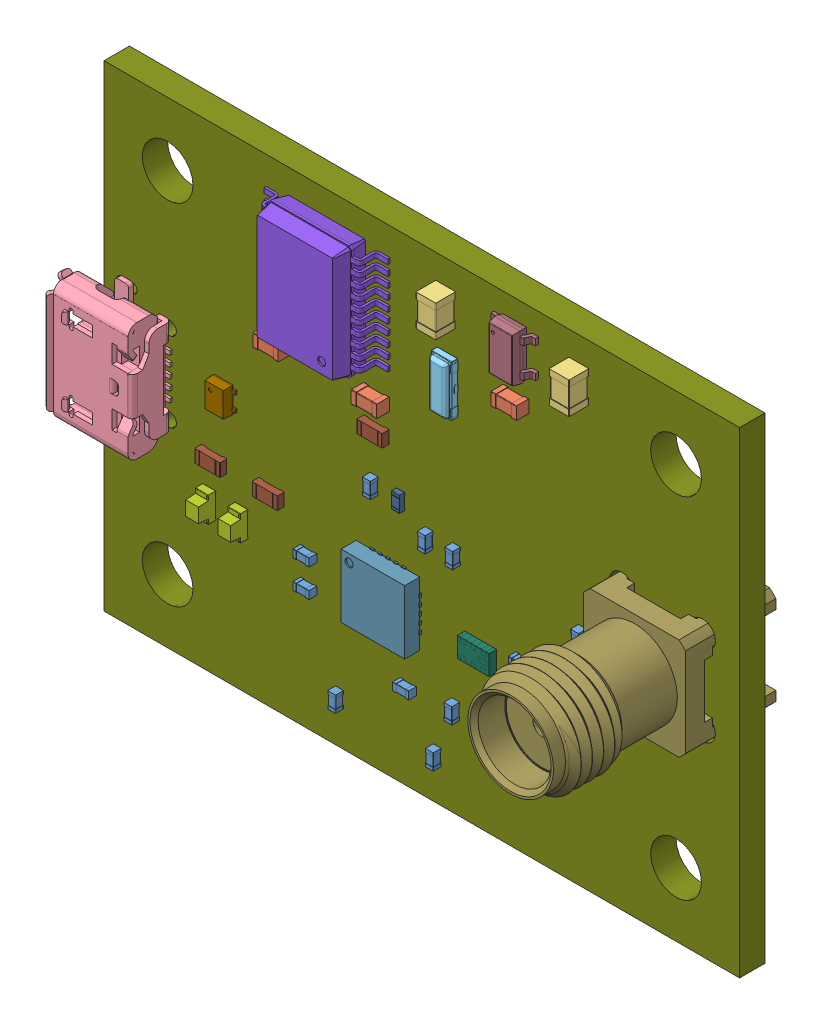
SolidWorks assembly EstacionTerrena, configuration Predeterminado. Lengths in mm.
Overall size (41.11 30 13.5).
69 component instances, 16 part files, 0 mates.
Components (placement in the parent):
- C_0402_1005Metric-1: C_0402_1005Metric [Predeterminado] at (26.5074 -19.4434 1.65) x (-1 0 0) z (0 0 1) size (1 0.5 0.5)
  - SOLID-1: SOLID [Predeterminado] at origin size (1 0.5 0.5)
- C_0402_1005Metric-2: C_0402_1005Metric [Predeterminado] at (29.2378 -21.2852 1.65) x (0 -1 0) z (0 0 1) size (1 0.5 0.5)
  - SOLID-1: SOLID [Predeterminado] at origin size (1 0.5 0.5)
- C_0402_1005Metric-3: C_0402_1005Metric [Predeterminado] at (30.1752 -16.256 1.65) x (0 1 0) z (0 0 1) size (1 0.5 0.5)
  - SOLID-1: SOLID [Predeterminado] at origin size (1 0.5 0.5)
- C_0603_1608Metric-1: C_0603_1608Metric [Predeterminado] at (11.0236 -9.7028 1.65) x (-1 0 0) z (0 0 1) size (1.6 0.8 0.8)
  - SOLID_2-1: SOLID_2 [Predeterminado] at origin size (1.6 0.8 0.8)
- C_0603_1608Metric-2: C_0603_1608Metric [Predeterminado] at (17.2212 -9.7028 1.65) x (-1 0 0) z (0 0 1) size (1.6 0.8 0.8)
  - SOLID_2-1: SOLID_2 [Predeterminado] at origin size (1.6 0.8 0.8)
- C_0603_1608Metric-3: C_0603_1608Metric [Predeterminado] at (26.0096 -5.4102 1.65) x (-1 0 0) z (0 0 1) size (1.6 0.8 0.8)
  - SOLID_2-1: SOLID_2 [Predeterminado] at origin size (1.6 0.8 0.8)
- C_0805_2012Metric-1: C_0805_2012Metric [Predeterminado] at (29.9466 -2.4892 1.65) x (0 -1 0) z (0 0 1) size (2 1.25 1.25)
  - SOLID_3-1: SOLID_3 [Predeterminado] at origin size (2 1.25 1.25)
- C_0805_2012Metric-2: C_0805_2012Metric [Predeterminado] at (21.5646 -2.4892 1.65) x (0 -1 0) z (0 0 1) size (2 1.25 1.25)
  - SOLID_3-1: SOLID_3 [Predeterminado] at origin size (2 1.25 1.25)
- USB_Micro-B_Molex_47346-0001-1: USB_Micro-B_Molex_47346-0001 [Predeterminado] at (2.681 -15.007 1.65) x (0 -1 0) z (0 0 1) size (7.98 5.42 2.94)
  - SOLID_4-1: SOLID_4 [Predeterminado] at origin size (7.98 5.42 2.94)
- CSTNE12M0GH5L000R0-1: CSTNE12M0GH5L000R0 [Predeterminado] at (21.6916 -6.6548 1.65) x (0 -1 0) z (-1 0 0) size (3.2 0.71 1.32)
  - SOLID_5-1: SOLID_5 [Predeterminado] at origin size (3.2 0.71 1.32)
- L_0402_1005Metric-1: L_0402_1005Metric [Predeterminado] at (30.8634 -19.4564 1.65) size (1 0.5 0.5)
  - SOLID_6-1: SOLID_6 [Predeterminado] at origin size (1 0.5 0.5)
- LED_0603_1608Metric-1: LED_0603_1608Metric [Predeterminado] at (8.7376 -20.6756 1.65) x (0 1 0) z (0 0 1) size (1.6 0.8 1.1)
  - SOLID_7-1: SOLID_7 [Predeterminado] at origin size (1.6 0.8 1.1)
- LED_0603_1608Metric-2: LED_0603_1608Metric [Predeterminado] at (6.7056 -20.6756 1.65) x (0 1 0) z (0 0 1) size (1.6 0.8 1.1)
  - SOLID_7-1: SOLID_7 [Predeterminado] at origin size (1.6 0.8 1.1)
- SSOP-20_5.3x7.2mm_P0.65mm-1: SSOP-20_5.3x7.2mm_P0.65mm [Predeterminado] at (14.1732 -4.7752 1.65) x (-1 0 0) z (0 0 1) size (7.8 7.2 2.1)
  - SOLID_8-1: SOLID_8 [Predeterminado] at origin size (7.8 7.2 2.1)
- SOT-553-1: SOT-553 [Predeterminado] at (7.62 -14.351 1.65) size (1.6 1.6 0.63)
  - SOLID_9-1: SOLID_9 [Predeterminado] at origin size (1.6 1.6 0.63)
- R_0402_1005Metric-1: R_0402_1005Metric [Predeterminado] at (28.7528 -19.4564 1.65) size (1 0.5 0.35)
  - SOLID_10-1: SOLID_10 [Predeterminado] at origin size (1 0.5 0.35)
- R_0402_1005Metric-2: R_0402_1005Metric [Predeterminado] at (29.8196 -18.0848 1.65) size (1 0.5 0.35)
  - SOLID_10-1: SOLID_10 [Predeterminado] at origin size (1 0.5 0.35)
- R_0603_1608Metric-1: R_0603_1608Metric [Predeterminado] at (17.2212 -11.4808 1.65) x (-1 0 0) z (0 0 1) size (1.6 0.8 0.45)
  - SOLID_11-1: SOLID_11 [Predeterminado] at origin size (1.6 0.8 0.45)
- R_0603_1608Metric-2: R_0603_1608Metric [Predeterminado] at (10.6172 -18.1864 1.65) x (-1 0 0) z (0 0 1) size (1.6 0.8 0.45)
  - SOLID_11-1: SOLID_11 [Predeterminado] at origin size (1.6 0.8 0.45)
- R_0603_1608Metric-3: R_0603_1608Metric [Predeterminado] at (7.0104 -18.1864 1.65) x (-1 0 0) z (0 0 1) size (1.6 0.8 0.45)
  - SOLID_11-1: SOLID_11 [Predeterminado] at origin size (1.6 0.8 0.45)
- 5-1814832-1-1: 5-1814832-1 [Predeterminado] at (35.1536 -14.9352 11.15) x (0 1 0) z (0 0 1) size (6.4 6.4 13.5)
  - SOLID_12-1: SOLID_12 [Predeterminado] at origin size (6.4 6.4 13.5)
- MIC5323-3.3YD5_TR-1: MIC5323-3.3YD5_TR [Predeterminado] at (26.0096 -2.4892 1.65) size (2.8 2.9 1)
  - COMPOUND-1: COMPOUND [Predeterminado] at origin size (2.8 2.9 1)
- CC1101RGP-1: CC1101RGP [Predeterminado] at (17.9832 -20.1168 1.65) size (4.1 4.1 1)
  - COMPOUND_2-1: COMPOUND_2 [Predeterminado] at origin size (4.1 4.1 1)
- 0915BM15A0001E-1: 0915BM15A0001E [Predeterminado] at (23.7236 -20.3668 1.65) x (-1 0 0) z (0 0 1) size (2 1.25 0.85)
  - COMPOUND_3-1: COMPOUND_3 [Predeterminado] at origin size (2 1.25 0.85)
- C_0402_1005Metric-4: C_0402_1005Metric [Predeterminado] at (12.954 -20.3708 1.65) x (-1 0 0) z (0 0 1) size (1 0.5 0.5)
  - SOLID-1: SOLID [Predeterminado] at origin size (1 0.5 0.5)
- C_0402_1005Metric-5: C_0402_1005Metric [Predeterminado] at (12.954 -22.1488 1.65) x (-1 0 0) z (0 0 1) size (1 0.5 0.5)
  - SOLID-1: SOLID [Predeterminado] at origin size (1 0.5 0.5)
- C_0402_1005Metric-6: C_0402_1005Metric [Predeterminado] at (17.0688 -14.515 1.65) x (0 1 0) z (0 0 1) size (1 0.5 0.5)
  - SOLID-1: SOLID [Predeterminado] at origin size (1 0.5 0.5)
- C_0402_1005Metric-7: C_0402_1005Metric [Predeterminado] at (14.8844 -27.2541 1.65) x (0 1 0) z (0 0 1) size (1 0.5 0.5)
  - SOLID-1: SOLID [Predeterminado] at origin size (1 0.5 0.5)
- C_0402_1005Metric-8: C_0402_1005Metric [Predeterminado] at (21.0312 -27.3304 1.65) x (0 -1 0) z (0 0 1) size (1 0.5 0.5)
  - SOLID-1: SOLID [Predeterminado] at origin size (1 0.5 0.5)
- C_0402_1005Metric-9: C_0402_1005Metric [Predeterminado] at (22.1996 -24.2316 1.65) x (0 -1 0) z (0 0 1) size (1 0.5 0.5)
  - SOLID-1: SOLID [Predeterminado] at origin size (1 0.5 0.5)
- C_0402_1005Metric-10: C_0402_1005Metric [Predeterminado] at (19.2279 -24.4856 1.65) size (1 0.5 0.5)
  - SOLID-1: SOLID [Predeterminado] at origin size (1 0.5 0.5)
- C_0402_1005Metric-11: C_0402_1005Metric [Predeterminado] at (22.2504 -15.748 1.65) x (0 1 0) z (0 0 1) size (1 0.5 0.5)
  - SOLID-1: SOLID [Predeterminado] at origin size (1 0.5 0.5)
- C_0402_1005Metric-12: C_0402_1005Metric [Predeterminado] at (20.5232 -15.748 1.65) x (0 1 0) z (0 0 1) size (1 0.5 0.5)
  - SOLID-1: SOLID [Predeterminado] at origin size (1 0.5 0.5)
- R_0402_1005Metric-3: R_0402_1005Metric [Predeterminado] at (18.7452 -14.515 1.65) x (0 -1 0) z (0 0 1) size (1 0.5 0.35)
  - SOLID_10-1: SOLID_10 [Predeterminado] at origin size (1 0.5 0.35)
- COMPOUND_4-1: COMPOUND_4 [Predeterminado] at origin size (40 30 1.6)
